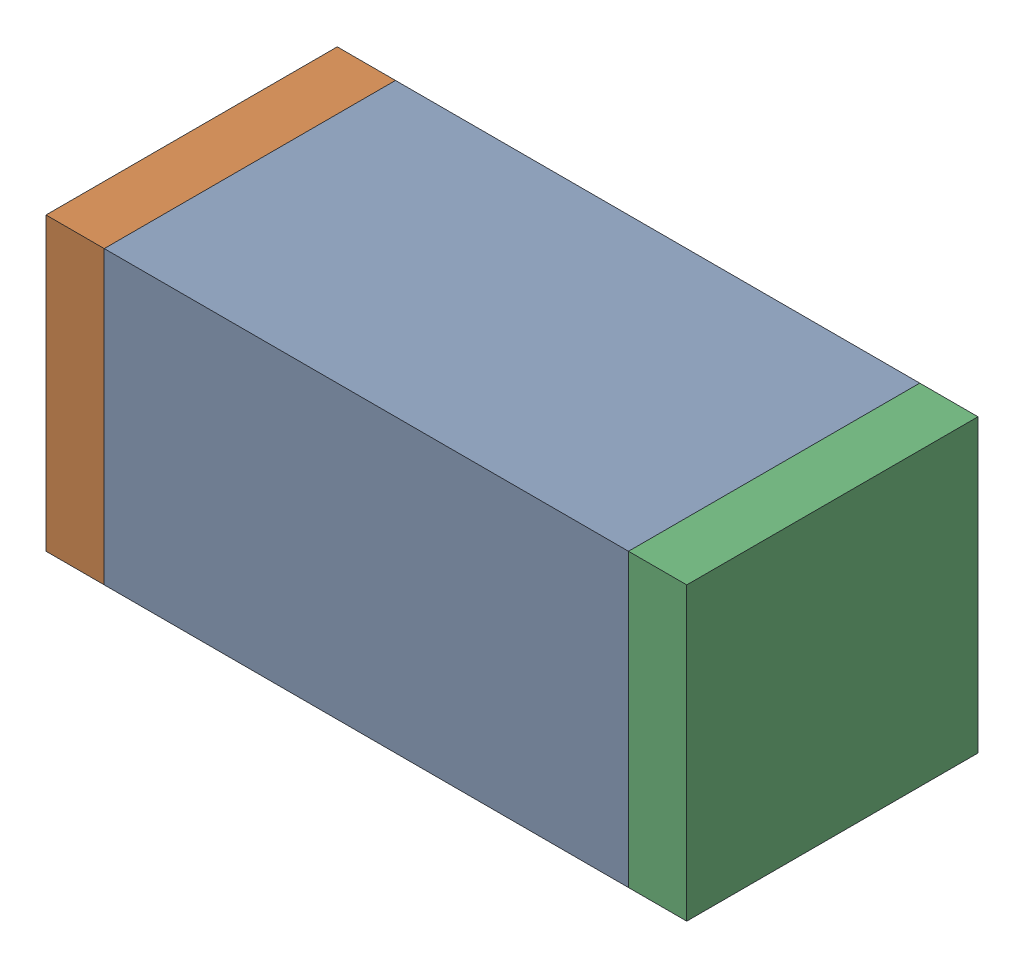
SolidWorks assembly C48, configuration Default. Lengths in mm.
Overall size (1.1 0.5 0.5).
6 component instances, 2 part files, 0 mates.
Components (placement in the parent):
- 836749680-1: 836749680 [Default] at (114.2 39.55 0) size (0.9 0.5 0.5)
  - Extruded_4-1: Extruded_4 [Default] at origin size (0.9 0.5 0.5)
- 810156080-1: 810156080 [Default] at (113.7 39.55 0) size (0.1 0.5 0.5)
  - Extruded_5-1: Extruded_5 [Default] at origin size (0.1 0.5 0.5)
- 810156080-2: 810156080 [Default] at (114.7 39.55 0) size (0.1 0.5 0.5)
  - Extruded_5-1: Extruded_5 [Default] at origin size (0.1 0.5 0.5)
